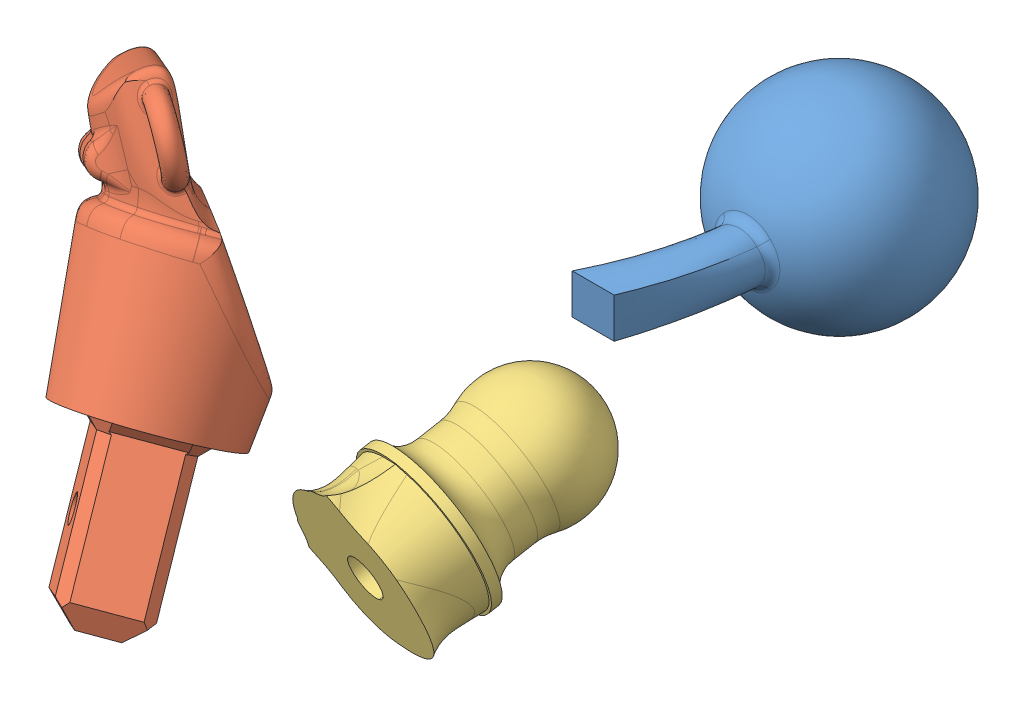
SolidWorks assembly Assem1, configuration Default. Lengths in mm.
Overall size (134.54 122.87 216.38).
3 component instances, 3 part files, 0 mates.
Components (placement in the parent):
- ball2-1: ball2 [Default] at (66.8525 36.2014 -22.9131) size (69.3 53.83 80.69)
- Femoral head attachments-1: Femoral head attachments [Default] at (86.794 -319.508 355.0648) x (-0.679675 -0.472585 -0.560985) z (0.728409 -0.344788 -0.592065) size (46.45 102.84 50.79)
- Femoral knob 011819-1: Femoral knob 011819 [Default] at (344.9458 -256.6077 349.0558) x (-0.491481 -0.793495 -0.358903) z (0.660799 -0.071344 -0.747164) size (38.14 57.65 59.92)
